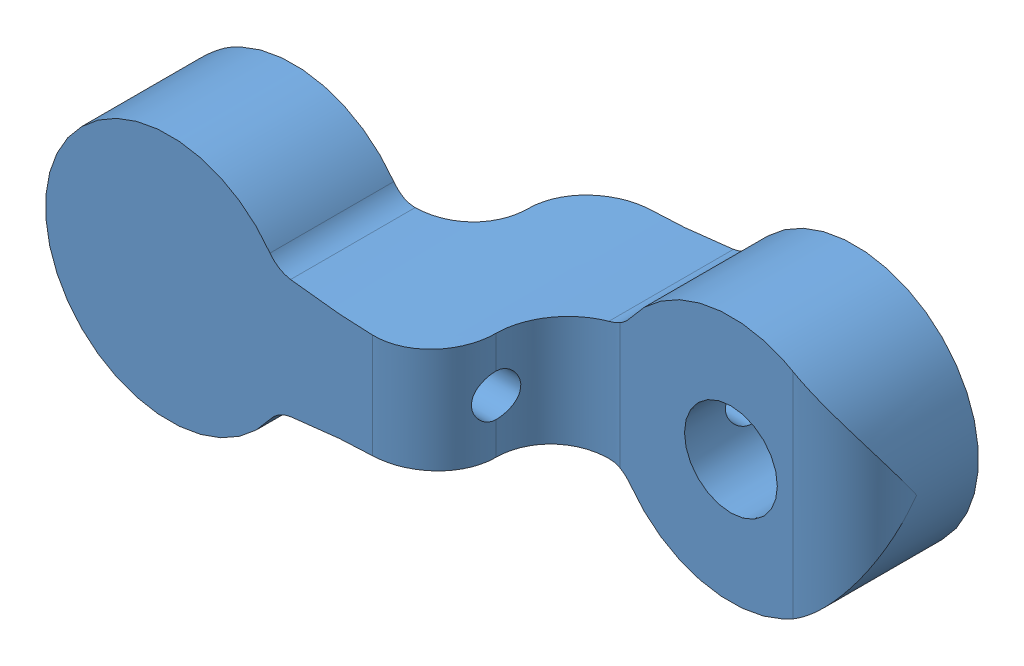
SolidWorks assembly 800-LinkwithOpenHole, configuration Default. Lengths in mm.
Overall size (70.32 25.4 25.4).
4 component instances, 3 part files, 9 mates.
Components (placement in the parent):
- 501-Link-1: 501-Link [Default] at origin size (70.32 25.4 25.4)
- 507-SSBallNoseSpringPlunger_MC-3408A95-1: 507-SSBallNoseSpringPlunger_MC-3408A95 [Default] at (27.178 0 0) x (0 0 -1) z (1 0 0) (suppressed, hidden)
- 504-Plug-1: 504-Plug [Default] at (34.925 0 0) x (0 0 -1) z (1 0 0) (suppressed, hidden)
- 507-SSBallNoseSpringPlunger_MC-3408A95-3: 507-SSBallNoseSpringPlunger_MC-3408A95 [Default] at (-17.8444 2.4517 12.2076) x (0 -0.3861 -0.922457) z (1 0 0)
Mates (geometry in assembly coordinates):
- InPlace1: in place: plane of 501-Link-1; plane of 507-SSBallNoseSpringPlunger_MC-3408A95-1; moOrthogonalPlaneRef_w of 501-Link-1; plane of 507-SSBallNoseSpringPlunger_MC-3408A95-1; moOrthogonalPlaneRef_w of 501-Link-1; plane of 507-SSBallNoseSpringPlunger_MC-3408A95-1
- Coincident1: coincident aligned: plane of 501-Link-1; plane of 507-SSBallNoseSpringPlunger_MC-3408A95-1
- Coincident2: coincident aligned: moOrthogonalPlaneRef_w of 501-Link-1; plane of 507-SSBallNoseSpringPlunger_MC-3408A95-1
- Coincident3: coincident anti-aligned: moOrthogonalPlaneRef_w of 501-Link-1; plane of 507-SSBallNoseSpringPlunger_MC-3408A95-1
- InPlace2: in place: plane of assembly; plane of 504-Plug-1; moOrthogonalPlaneRef_w of assembly; plane of 504-Plug-1; moOrthogonalPlaneRef_w of assembly; plane of 504-Plug-1
- Coincident4: coincident aligned: plane of 504-Plug-1; plane of assembly
- Coincident5: coincident aligned: plane of 504-Plug-1; moOrthogonalPlaneRef_w of assembly
- Coincident6: coincident anti-aligned: plane of 504-Plug-1; moOrthogonalPlaneRef_w of assembly
- Concentric1: concentric aligned: cylinder of 501-Link-1 through (35.16 0 6.35) axis (-1 0 0) radius 2.159; cylinder of 507-SSBallNoseSpringPlunger_MC-3408A95-3 through (-4.8142 0 6.35) axis (-1 0 0) radius 2.413
